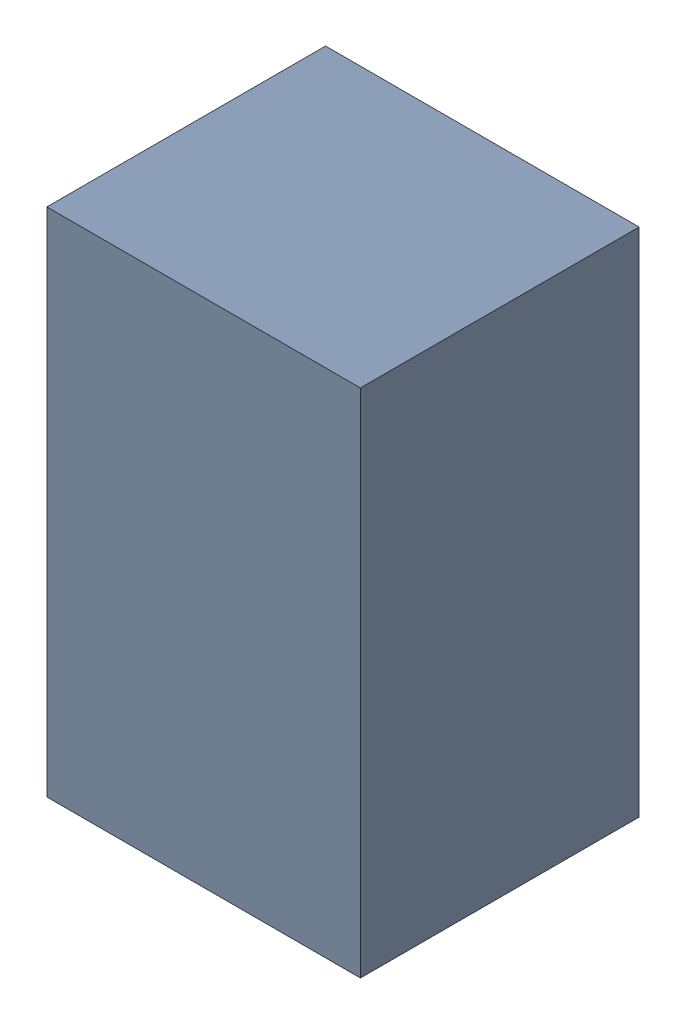
SolidWorks assembly CP2, configuration Default. Lengths in mm.
Overall size (1.35 2.2 1.2).
2 component instances, 1 part files, 0 mates.
Components (placement in the parent):
- 407985568-1: 407985568 [Default] at (77.5208 61.3918 -1.6039) size (1.35 2.2 1.2)
  - Extruded_3-1: Extruded_3 [Default] at origin size (1.35 2.2 1.2)
